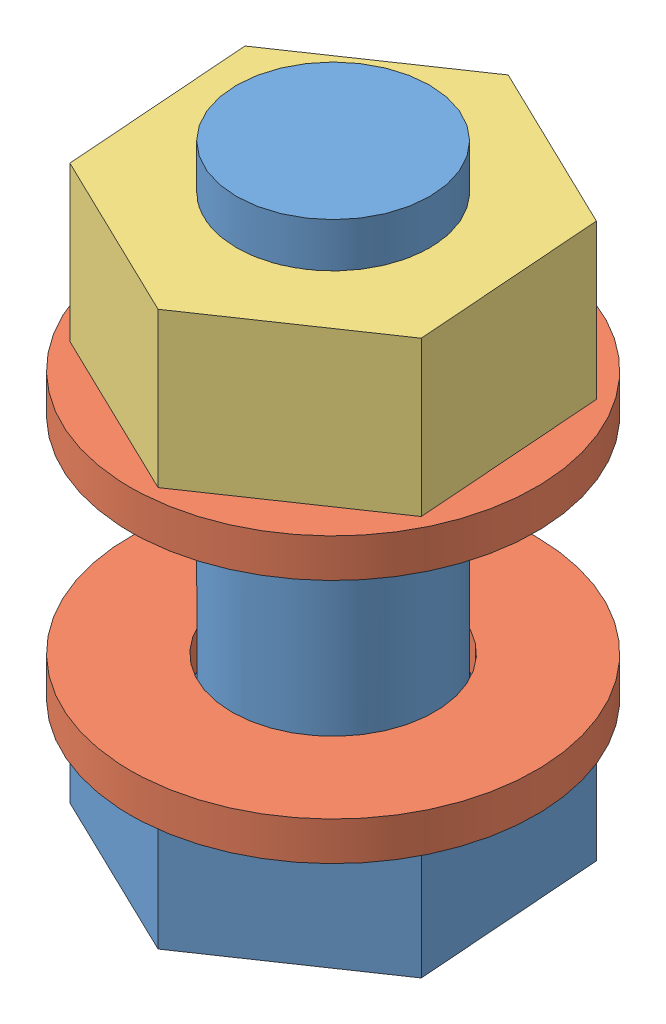
SolidWorks assembly PUTM-S-TR-GR-Rack-Bolt-Assembly, configuration Domyślna. Lengths in mm.
Overall size (21.76 31 21.93).
4 component instances, 3 part files, 7 mates.
Components (placement in the parent):
- PUTM-S-TR-GR-DiffBolt-1: PUTM-S-TR-GR-DiffBolt [Domyślna] at (-23.4594 -19.9739 19.7605) size (17.68 31 19.58)
- PUTM-S-TR-GR-Washer-1: PUTM-S-TR-GR-Washer [Domyślna] at (-23.4594 -19.9739 19.7605) size (21 2 21)
- PUTM-S-TR-GR-DiffNut-1: PUTM-S-TR-GR-DiffNut [Domyślna] at (-23.4594 -5.2739 19.7605) x (0.986077 0 0.166287) z (-0.166287 0 0.986077) size (18.85 8 19.06)
- PUTM-S-TR-GR-Washer-2: PUTM-S-TR-GR-Washer [Domyślna] at (-23.4594 -7.2739 19.7605) size (21 2 21)
Mates (geometry in assembly coordinates):
- Koncentryczne1: concentric aligned: cylinder of PUTM-EV-DT-DiffBolt-1 through (-23.4594 5.0261 19.7605) axis (0 -1 0) radius 5; cylinder of PUTM-EV-DT-Washer-1 through (-23.4594 -17.9739 19.7605) axis (0 -1 0) radius 5.25
- Wspólnie1: coincident anti-aligned: plane of PUTM-EV-DT-DiffBolt-1 through (-23.4594 -19.9739 19.7605) normal (0 1 0); plane of PUTM-EV-DT-Washer-1 through (-23.4594 -19.9739 19.7605) normal (0 -1 0)
- Koncentryczne2: concentric aligned: cylinder of PUTM-EV-DT-DiffBolt-1 through (-23.4594 5.0261 19.7605) axis (0 -1 0) radius 5; cylinder of PUTM-EV-DT-Washer-2 through (-23.4594 -5.2739 19.7605) axis (0 -1 0) radius 5.25
- Odległość1: distance = 10.7 mm anti-aligned: plane of PUTM-EV-DT-Washer-1 through (-23.4594 -17.9739 19.7605) normal (0 1 0); plane of PUTM-EV-DT-Washer-2 through (-23.4594 -7.2739 19.7605) normal (0 -1 0)
- Wspólnie3: coincident anti-aligned: plane of PUTM-E-DV-DiffNut-1 through (-23.4594 -5.2739 19.7605) normal (0 -1 0); plane of PUTM-EV-DT-Washer-2 through (-23.4594 -5.2739 19.7605) normal (0 1 0)
- Koncentryczne3: concentric aligned: cylinder of PUTM-EV-DT-DiffBolt-1 through (-23.4594 5.0261 19.7605) axis (0 -1 0) radius 5; cylinder of PUTM-E-DV-DiffNut-1 through (-23.4594 2.7261 19.7605) axis (0 -1 0) radius 5
- Wspólnie4: coincident aligned: plane of PUTM-EV-DT-DiffBolt-1 through (-14.6219 -25.9739 24.0302) normal (0.562276 0 0.82695); plane of PUTM-E-DV-DiffNut-1 through (-22.7383 2.7261 29.5489) normal (0.562276 0 0.82695)
